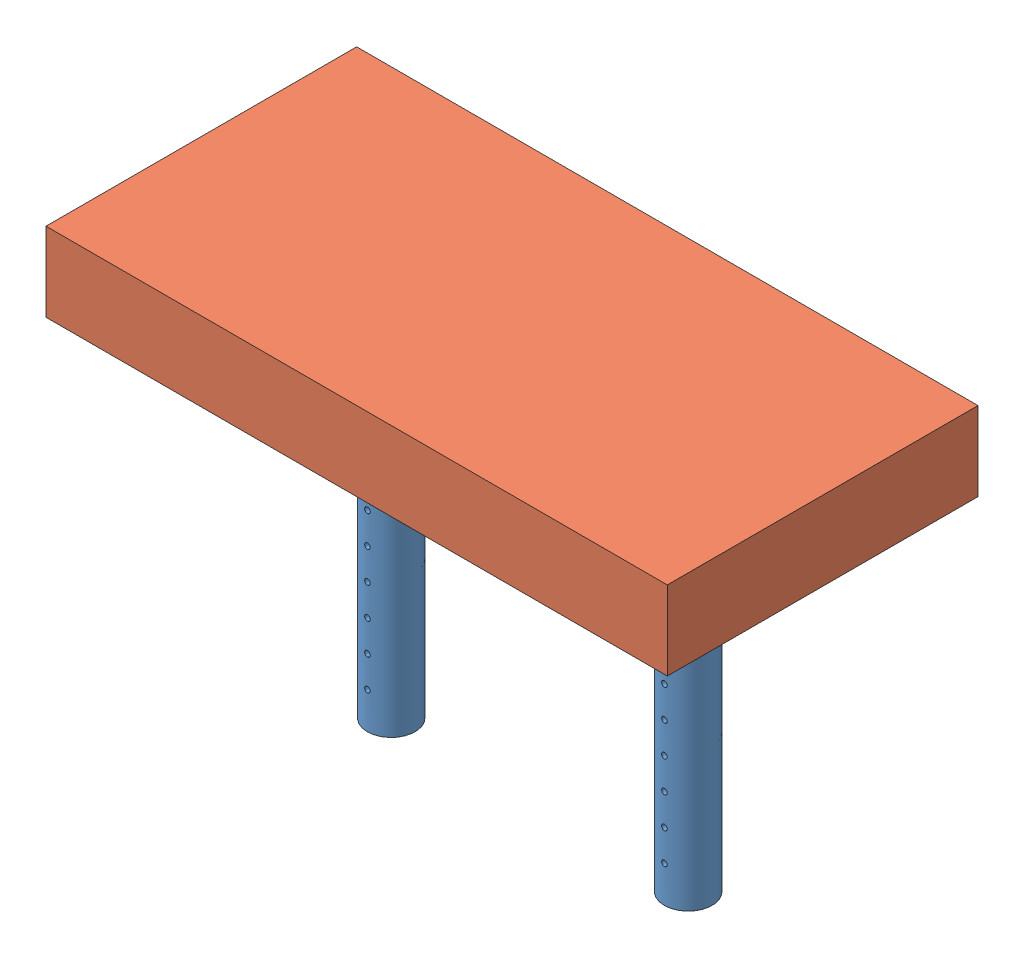
SolidWorks assembly Assem1, configuration Default. Lengths in mm.
Overall size (100 66.41 50).
3 component instances, 2 part files, 2 mates.
Components (placement in the parent):
- Attachment Leg-1: Attachment Leg [Default] at (-69.0327 70.1269 30.7233) x (-1 0 0) z (0 0 1) size (7.7 44.45 7.7)
- Attachment Leg-9: Attachment Leg [Default] at (-21.2327 69.8191 30.7233) x (-1 0 0) z (0 0 1) size (7.7 44.45 7.7)
- Attachment Plate-1: Attachment Plate [Default] at (-49.2603 91.7818 31.058) x (0 0 1) z (1 0 0) size (50 12.7 100)
Mates (geometry in assembly coordinates):
- Parallel7: parallel aligned: plane of Attachment Leg-1 through (-69.0327 25.6769 30.7233) normal (0 -1 0); plane of Attachment Leg-9 through (-21.2327 25.3691 30.7233) normal (0 -1 0)
- Distance4: distance = 40.1 mm: cylinder of Attachment Leg-1 through (-69.0327 25.6769 30.7233) axis (0 1 0) radius 3.85; cylinder of Attachment Leg-9 through (-21.2327 25.3691 30.7233) axis (0 1 0) radius 3.85
